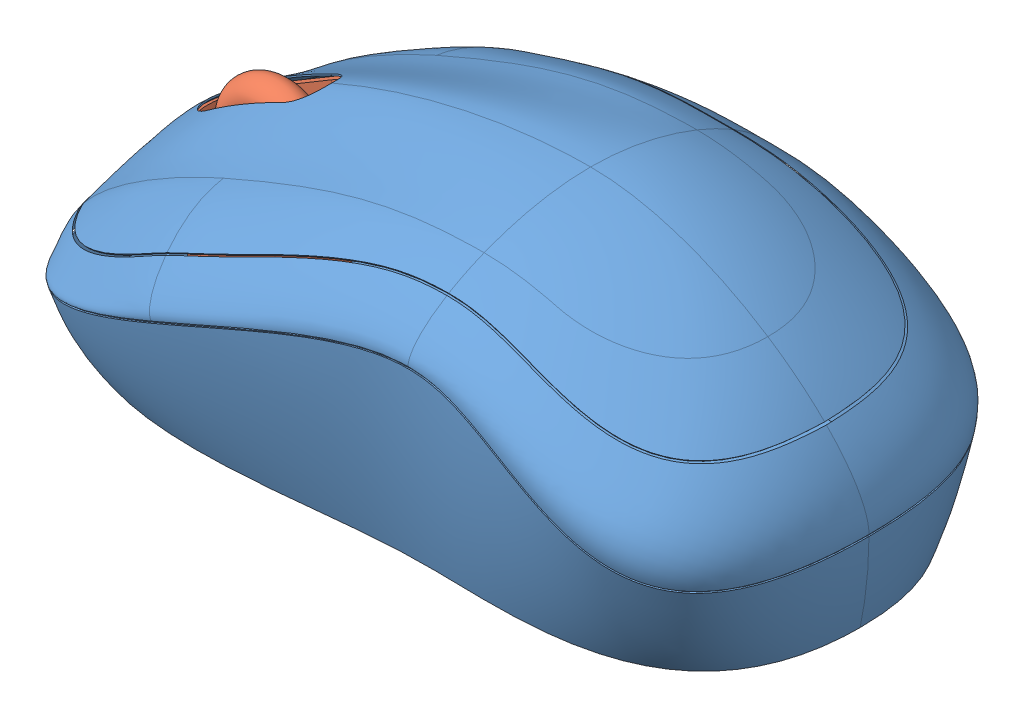
SolidWorks assembly 鼠标3装配体1, configuration Default. Lengths in mm.
Overall size (108.46 38.7 60.93).
2 component instances, 2 part files, 3 mates.
Components (placement in the parent):
- 鼠标3-1: 鼠标3 [默认] at origin size (108.46 38.7 60.93)
- 鼠标3_滚轮-1: 鼠标3_滚轮 [默认] at (-39.75 0.21 0) size (19.5 28.6 9)
Mates (geometry in assembly coordinates):
- 重合4: coincident anti-aligned: plane of 鼠标3-1 through (-29.25 0.21 0) normal (0 1 0); plane of 鼠标3_滚轮-1 through (-39.75 0.21 0) normal (0 -1 0)
- 重合5: coincident anti-aligned: line of 鼠标3-1 through (-29.25 0.21 3.5) axis (-1 0 0); line of 鼠标3_滚轮-1 through (-39.75 0.21 3.5) axis (1 0 0)
- 同心1: concentric aligned: circle of 鼠标3-1; circle of 鼠标3_滚轮-1
